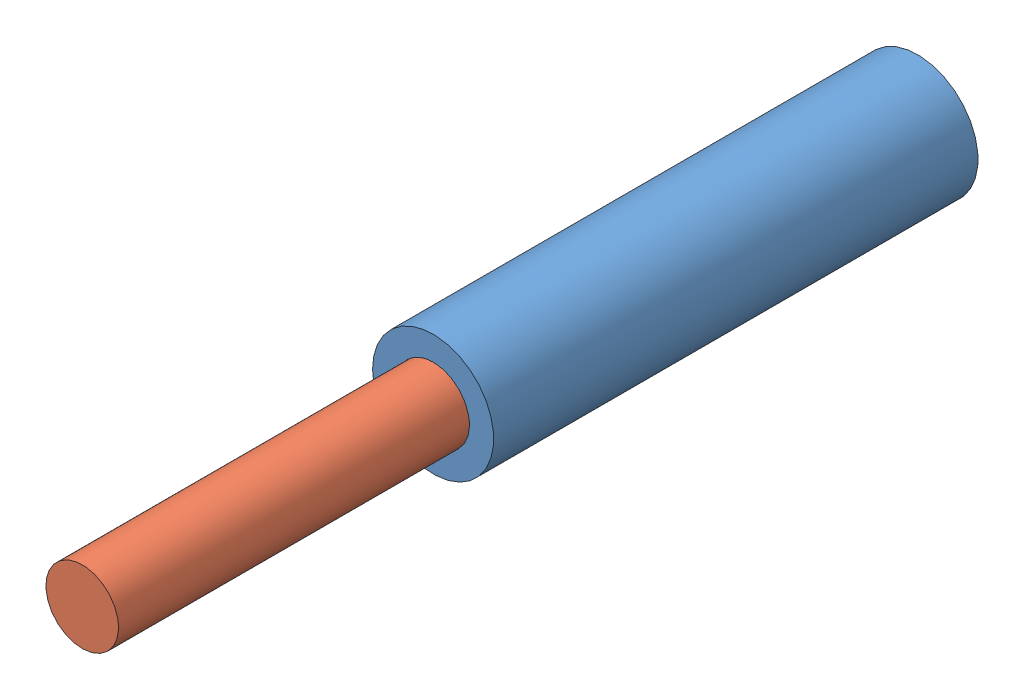
SolidWorks assembly Assem1, configuration Default. Lengths in mm.
Overall size (5 5 34.49).
2 component instances, 2 part files, 1 mates.
Components (placement in the parent):
- circle part 1-1: circle part 1 [Default] at (10.8901 15.2628 10.2661) size (5 5 20)
- Circle Part2-1: Circle Part2 [Default] at (10.8901 15.2628 24.7557) x (0.996499 0.083609 0) z (0 0 1) size (3 3 20)
Mates (geometry in assembly coordinates):
- Concentric1: concentric aligned: cylinder of circle part 1-1 through (10.8901 15.2628 30.2661) axis (0 0 -1) radius 1.5; cylinder of Circle Part2-1 through (10.8901 15.2628 44.7557) axis (0 0 -1) radius 1.5
